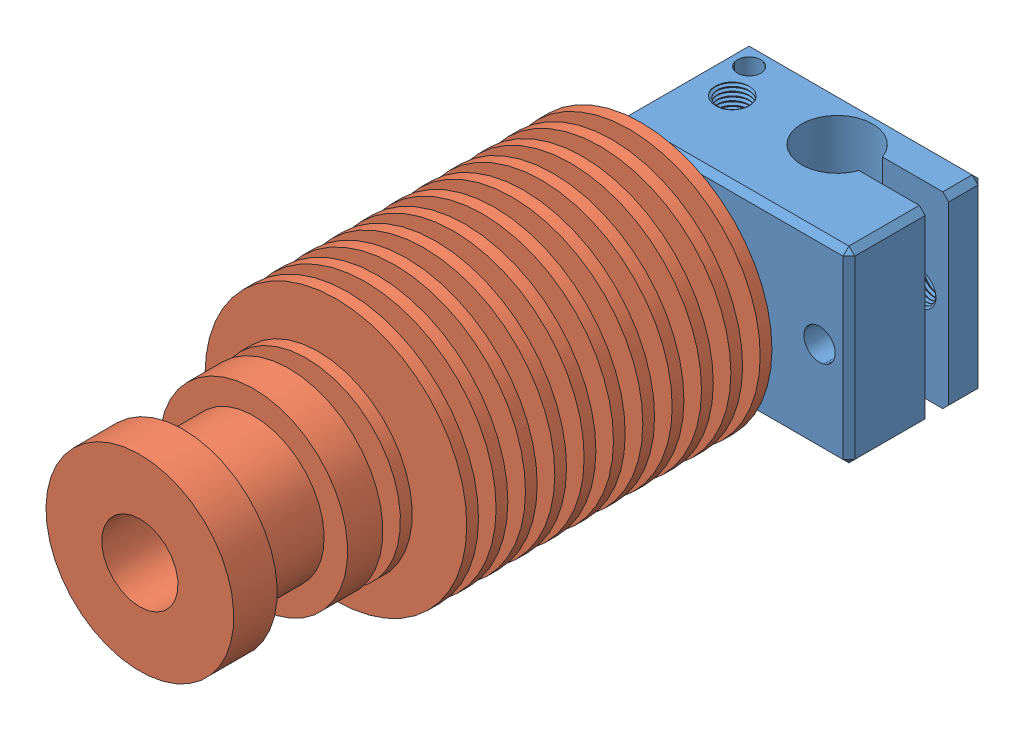
SolidWorks assembly e3d_v6_175, configuration Default. Lengths in mm.
Overall size (28.15 25.09 61.3).
4 component instances, 4 part files, 7 mates.
Components (placement in the parent):
- Heaterblock.stp-1: Heaterblock.stp [Default] at (45.073 9.7855 4.6892) size (20 16.05 11.6)
- Heatsink.stp-1: Heatsink.stp [Default] at (11.1849 26.0506 18.2892) x (0.990938 -0.134318 0) z (0 0 1) size (22.3 22.3 42.75)
- Nozzle 0.4mm.stp-1: Nozzle 0.4mm.stp [Default] at (26.1197 -35.9963 1.6892) x (0.866025 -0.5 0) z (0 0 1) size (8.08 7 12.54)
- Heatbreak.stp-1: Heatbreak.stp [Default] at (4.469 -23.4963 11.1892) size (7.03 7.04 22.45)
Mates (geometry in assembly coordinates):
- Concentric1: concentric aligned: circle of Heaterblock.stp-1; circle of Nozzle 0.4mm.stp-1
- Coincident2: coincident anti-aligned: plane of Heaterblock.stp-1 through (10.073 -23.2145 4.6892) normal (0 0 -1); plane of Nozzle 0.4mm.stp-1 through (4.469 -23.4963 4.6892) normal (0 0 1)
- Parallel1: parallel aligned: plane of Heaterblock.stp-1 through (0.073 -23.2145 10.4392) normal (-1 0 0); plane of Nozzle 0.4mm.stp-1 through (0.969 -21.4756 1.6892) normal (-1 0 0)
- Concentric2: concentric anti-aligned: circle of Heaterblock.stp-1; circle of Heatbreak.stp-1
- Coincident4: coincident aligned: plane of Heaterblock.stp-1 through (10.073 -23.2145 16.1892) normal (0 0 1); plane of Heatbreak.stp-1 through (4.469 -23.4963 16.1892) normal (0 0 1)
- Concentric3: concentric anti-aligned: circle of Heaterblock.stp-1; circle of Heatsink.stp-1
- Coincident5: coincident aligned: plane of Heatsink.stp-1 through (4.469 -23.4963 18.2892) normal (0 0 -1); plane of Heatbreak.stp-1 through (4.469 -23.4963 18.2892) normal (0 0 -1)
